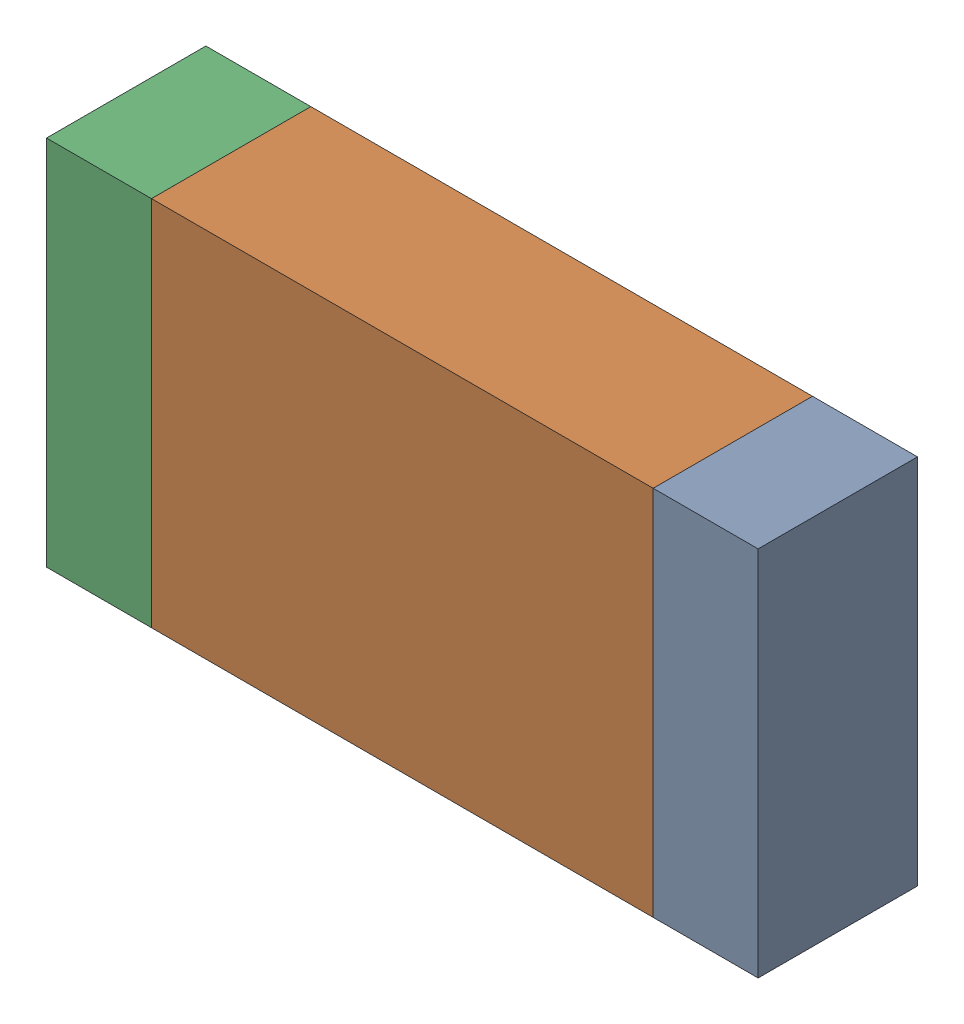
SolidWorks assembly R01, configuration Default. Lengths in mm.
Overall size (3.35 1.75 0.75).
6 component instances, 2 part files, 0 mates.
Components (placement in the parent):
- 959206760-1: 959206760 [Default] at (117.3285 91.9479 0) size (0.49 1.75 0.75)
  - Extruded-2-1: Extruded-2 [Default] at origin size (0.49 1.75 0.75)
- 959206896-1: 959206896 [Default] at (115.901 91.9479 0) size (2.36 1.75 0.75)
  - Extruded-3-1: Extruded-3 [Default] at origin size (2.36 1.75 0.75)
- 959206760-2: 959206760 [Default] at (114.4735 91.9479 0) size (0.49 1.75 0.75)
  - Extruded-2-1: Extruded-2 [Default] at origin size (0.49 1.75 0.75)
